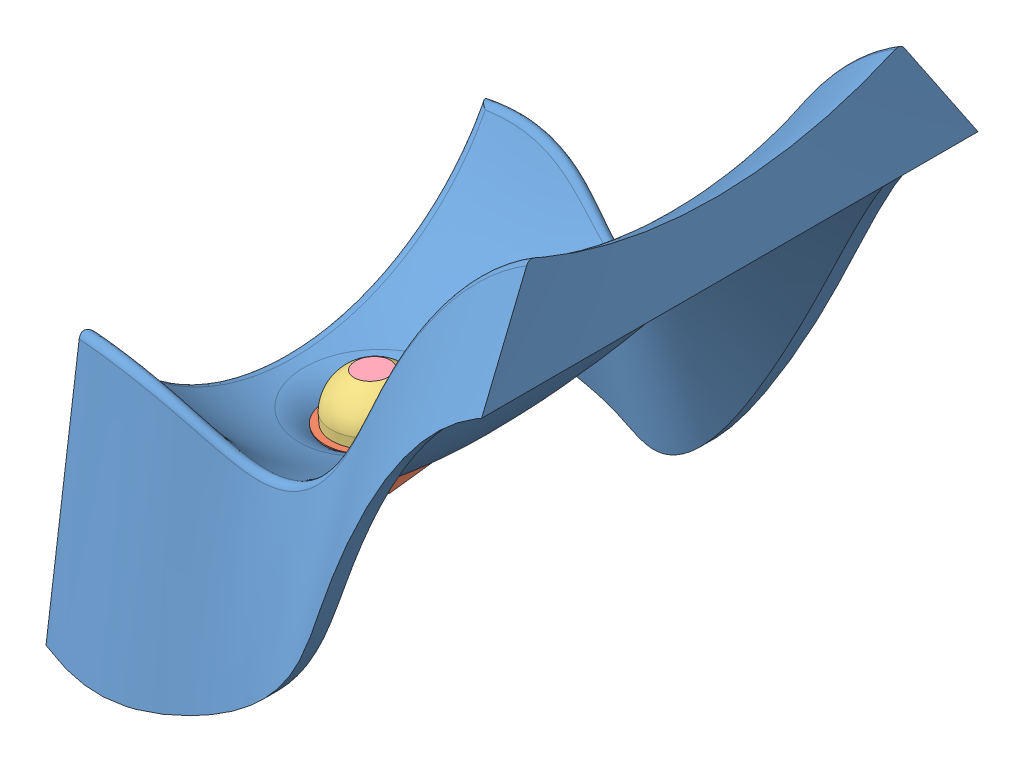
SolidWorks assembly Magnetic Force Sensor with Casing Assembly, configuration Default. Lengths in mm.
Overall size (68.77 82.29 78.14).
4 component instances, 4 part files, 4 mates.
Components (placement in the parent):
- Funnel with Opening for Elastomer-1: Funnel with Opening for Elastomer [Default] at (-37.7843 -40.7454 17.3257) size (68.77 82.29 78.14)
- Elastomer PCB Interface-1: Elastomer PCB Interface [Default] at (-26.1092 -46.4544 17.3299) x (0.988057 0.086959 -0.127205) z (0.126049 0.018684 0.991848) size (14 3.2 14)
- Silicon Elastomer-1: Silicon Elastomer [Default] at (-26.251 -44.8607 17.3179) x (0.996065 0.088627 -0.000333) z (0.088627 -0.996037 0.0075) size (12 12 7.9)
- Neodymium Magnet-2: Neodymium Magnet [Default] at (-26.7739 -38.9841 17.2736) x (0.996065 0.088627 -0.000333) z (-0.000333 0.0075 0.999972) size (5 2 5)
Mates (geometry in assembly coordinates):
- Concentric3: concentric anti-aligned: cylinder of Elastomer PCB Interface-1 through (-26.3928 -43.2671 17.3059) axis (0.088627 -0.996037 0.0075) radius 6; cylinder of Silicon Elastomer-1 through (-26.7739 -38.9841 17.2736) axis (-0.088627 0.996037 -0.0075) radius 6
- Coincident1: coincident: line of Elastomer PCB Interface-1 through (-27.1333 -44.9915 10.3749) axis (-0.988057 -0.086959 0.127205); plane of Silicon Elastomer-1 through (-26.251 -44.8607 17.3179) normal (0.088627 -0.996037 0.0075)
- Coincident4: coincident anti-aligned: plane of Silicon Elastomer-1 through (-26.7739 -38.9841 17.2736) normal (-0.088627 0.996037 -0.0075); plane of Neodymium Magnet-2 through (-26.7739 -38.9841 17.2736) normal (0.088627 -0.996037 0.0075)
- Concentric4: concentric anti-aligned: cylinder of Silicon Elastomer-1 through (-26.7739 -38.9841 17.2736) axis (-0.088627 0.996037 -0.0075) radius 2.5; cylinder of Neodymium Magnet-2 through (-26.9511 -36.992 17.2586) axis (0.088627 -0.996037 0.0075) radius 2.5
